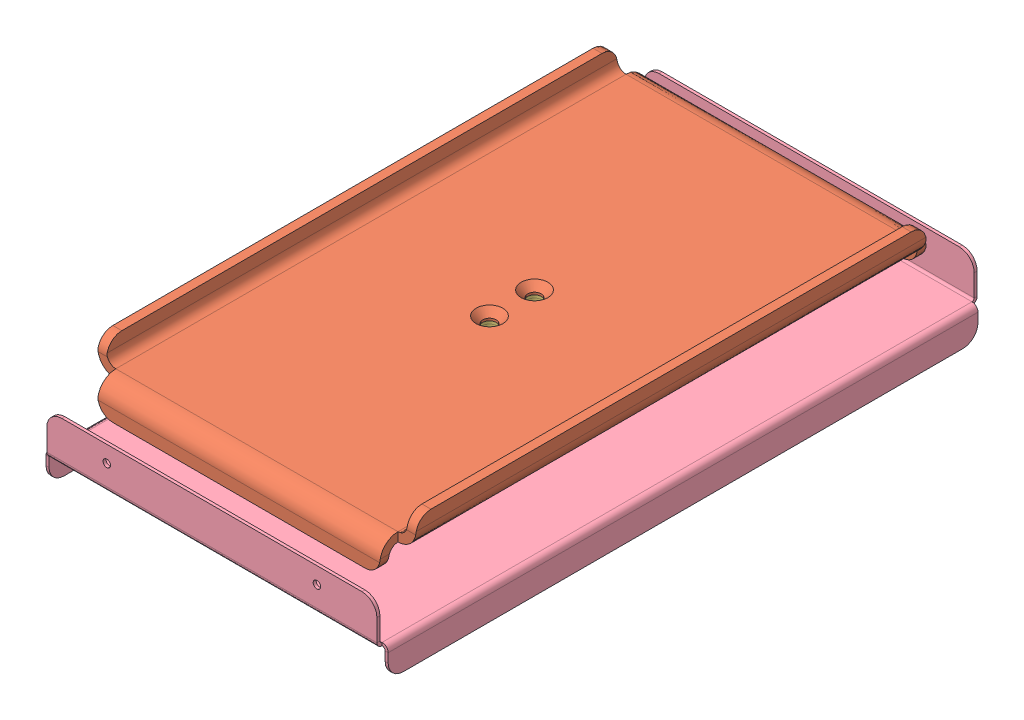
SolidWorks assembly T00004-000-R00, configuration Default. Lengths in mm.
Overall size (114 38.3 200).
11 component instances, 4 part files, 25 mates.
Components (placement in the parent):
- T00157-E00-R00-1: T00157-E00-R00 [Default] at (0 9.15 27.5) x (0 0 -1) z (-1 0 0) size (80 12.7 12.7)
- T00156-000-R00-1: T00156-000-R00 [Default] at (0 20.3 0) x (-1 0 0) z (0 1 0) size (106 182 17)
- flat washer narrow_am-1: flat washer narrow_am [B18.22M - Plain washer, 5 mm, narrow] at (0 2.8 62.5) x (0 1 0) z (0 0 1) size (1.4 11 11)
- flat washer narrow_am-2: flat washer narrow_am [B18.22M - Plain washer, 5 mm, narrow] at (0 2.8 47.5) x (0 1 0) z (0 0 1) size (1.4 11 11)
- flat washer narrow_am-3: flat washer narrow_am [B18.22M - Plain washer, 5 mm, narrow] at (0 1.4 62.5) x (0 1 0) z (0 0 1) size (1.4 11 11)
- flat washer narrow_am-4: flat washer narrow_am [B18.22M - Plain washer, 5 mm, narrow] at (0 1.4 47.5) x (0 1 0) z (-0.546944 0 0.837169) size (1.4 11 11)
- flat washer narrow_am-7: flat washer narrow_am [B18.22M - Plain washer, 5 mm, narrow] at (0 15.5 -7.5) x (0 -1 0) z (-0.546944 0 0.837169) size (1.4 11 11)
- flat washer narrow_am-8: flat washer narrow_am [B18.22M - Plain washer, 5 mm, narrow] at (0 16.9 -7.5) x (0 -1 0) z (0 0 1) size (1.4 11 11)
- flat washer narrow_am-11: flat washer narrow_am [B18.22M - Plain washer, 5 mm, narrow] at (0 15.5 7.5) x (0 -1 0) z (-0.535309 0 -0.844656) size (1.4 11 11)
- flat washer narrow_am-12: flat washer narrow_am [B18.22M - Plain washer, 5 mm, narrow] at (0 16.9 7.5) x (0 -1 0) z (0 0 1) size (1.4 11 11)
- T00155-0A3-R00-3: T00155-0A3-R00 [Default] x (0 0 -1) z (0 1 0) size (200 114 23)
Mates (geometry in assembly coordinates):
- Coincident7: coincident: plane of T00156-000-R00-1 through (0 20.3 0) normal (0 0 1); plane of assembly through (0 0 0) normal (0 0 1)
- Coincident8: coincident: plane of T00156-000-R00-1 through (0 20.3 0) normal (-1 0 0); plane of assembly through (0 0 0) normal (1 0 0)
- Concentric20: concentric: cylinder of T00157-E00-R00-1 through (0 2.8 62.5) axis (0 -1 0) radius 1.65; cylinder of flat washer narrow_am-1 through (0 -32.125 62.5) axis (0 -1 0) radius 2.89
- Coincident23: coincident: plane of T00157-E00-R00-1 through (0 2.8 27.5) normal (0 -1 0); plane of flat washer narrow_am-1 through (-2.89 2.8 62.5) normal (0 1 0)
- Concentric21: concentric: cylinder of T00157-E00-R00-1 through (0 2.8 47.5) axis (0 -1 0) radius 2.1; cylinder of flat washer narrow_am-2 through (0 -32.125 47.5) axis (0 -1 0) radius 2.89
- Coincident24: coincident: plane of T00157-E00-R00-1 through (0 2.8 27.5) normal (0 -1 0); plane of flat washer narrow_am-2 through (-2.89 2.8 47.5) normal (0 1 0)
- Concentric22: concentric: cylinder of flat washer narrow_am-1 through (0 -32.125 62.5) axis (0 -1 0) radius 2.89; cylinder of flat washer narrow_am-3 through (0 -33.525 62.5) axis (0 -1 0) radius 2.89
- Coincident25: coincident: plane of flat washer narrow_am-1 through (-5.5 1.4 62.5) normal (0 -1 0); plane of flat washer narrow_am-3 through (-2.89 1.4 62.5) normal (0 1 0)
- Concentric23: concentric: cylinder of flat washer narrow_am-2 through (0 -32.125 47.5) axis (0 -1 0) radius 2.89; cylinder of flat washer narrow_am-4 through (0 -33.525 47.5) axis (0 -1 0) radius 2.89
- Coincident26: coincident: plane of flat washer narrow_am-2 through (-5.5 1.4 47.5) normal (0 -1 0); plane of flat washer narrow_am-4 through (-2.4194 1.4 45.9193) normal (0 1 0)
- Concentric26: concentric: cylinder of T00157-E00-R00-1 through (0 2.8 -7.5) axis (0 -1 0) radius 1.65; cylinder of flat washer narrow_am-7 through (0 50.425 -7.5) axis (0 1 0) radius 2.89
- Coincident29: coincident: plane of T00157-E00-R00-1 through (0 15.5 27.5) normal (0 1 0); plane of flat washer narrow_am-7 through (2.4194 15.5 -5.9193) normal (0 -1 0)
- Concentric27: concentric: cylinder of flat washer narrow_am-7 through (0 50.425 -7.5) axis (0 1 0) radius 2.89; cylinder of flat washer narrow_am-8 through (0 51.825 -7.5) axis (0 1 0) radius 2.89
- Coincident30: coincident: plane of flat washer narrow_am-7 through (4.6044 16.9 -4.4918) normal (0 1 0); plane of flat washer narrow_am-8 through (2.89 16.9 -7.5) normal (0 -1 0)
- Concentric30: concentric: cylinder of T00157-E00-R00-1 through (0 2.8 7.5) axis (0 -1 0) radius 2.1; cylinder of flat washer narrow_am-11 through (0 50.425 7.5) axis (0 1 0) radius 2.89
- Coincident32: coincident: plane of T00157-E00-R00-1 through (0 15.5 27.5) normal (0 1 0); plane of flat washer narrow_am-11 through (-2.4411 15.5 9.047) normal (0 -1 0)
- Concentric31: concentric: cylinder of flat washer narrow_am-11 through (0 50.425 7.5) axis (0 1 0) radius 5.5; cylinder of flat washer narrow_am-12 through (0 51.825 7.5) axis (0 1 0) radius 2.89
- Coincident33: coincident: plane of flat washer narrow_am-11 through (-4.6456 16.9 10.4442) normal (0 1 0); plane of flat washer narrow_am-12 through (2.89 16.9 7.5) normal (0 -1 0)
- Coincident36: coincident: plane of T00156-000-R00-1 through (0 18.3 0) normal (0 -1 0); plane of flat washer narrow_am-8 through (5.5 18.3 -7.5) normal (0 1 0)
- Concentric33: concentric: circle of T00156-000-R00-1; circle of flat washer narrow_am-8
- Concentric34: concentric: circle of T00156-000-R00-1; circle of flat washer narrow_am-12
- Coincident46: coincident: plane of flat washer narrow_am-3 through (-5.5 0 62.5) normal (0 -1 0); plane of T00155-0A3-R00-3 through (0 0 0) normal (0 1 0)
- Coincident47: coincident: plane of T00155-0A3-R00-3 through (0 0 0) normal (0 0 -1); plane of assembly through (0 0 0) normal (0 0 1)
- Coincident48: coincident: plane of T00155-0A3-R00-3 through (0 0 0) normal (0 1 0); plane of assembly through (0 0 0) normal (0 1 0)
- Coincident49: coincident: plane of T00155-0A3-R00-3 through (0 0 0) normal (-1 0 0); plane of assembly through (0 0 0) normal (1 0 0)
